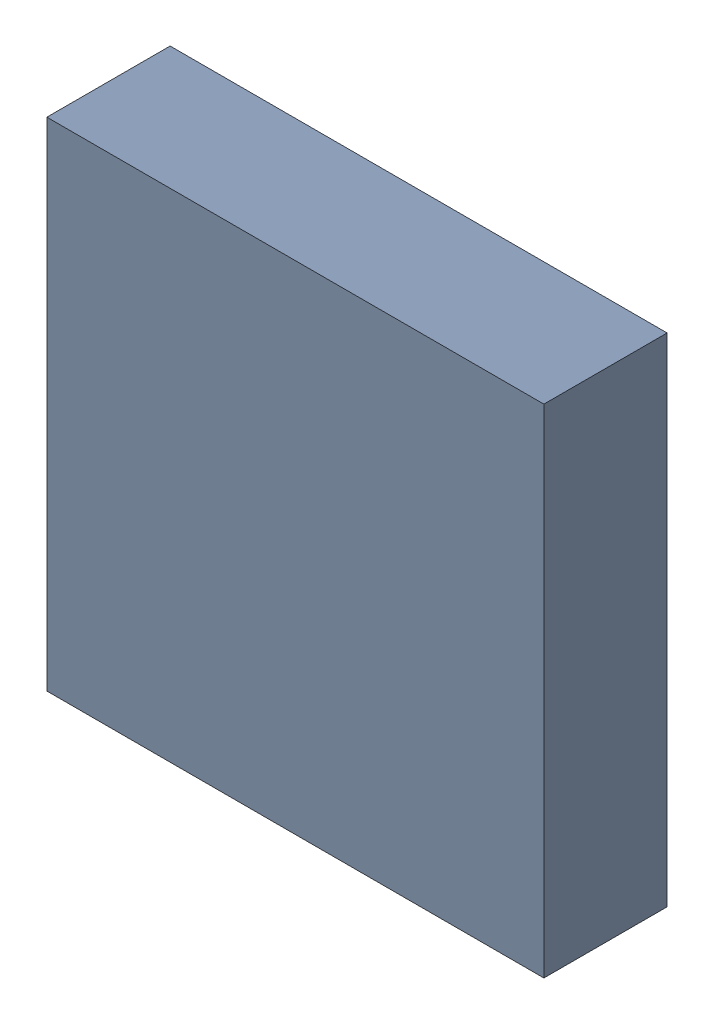
SolidWorks assembly U6, configuration Default. Lengths in mm.
Overall size (6.25 6.25 1.55).
2 component instances, 1 part files, 0 mates.
Components (placement in the parent):
- 870945760-1: 870945760 [Default] at (64.3882 17.1936 0.37) size (6.25 6.25 1.55)
  - Extruded_41-1: Extruded_41 [Default] at origin size (6.25 6.25 1.55)
